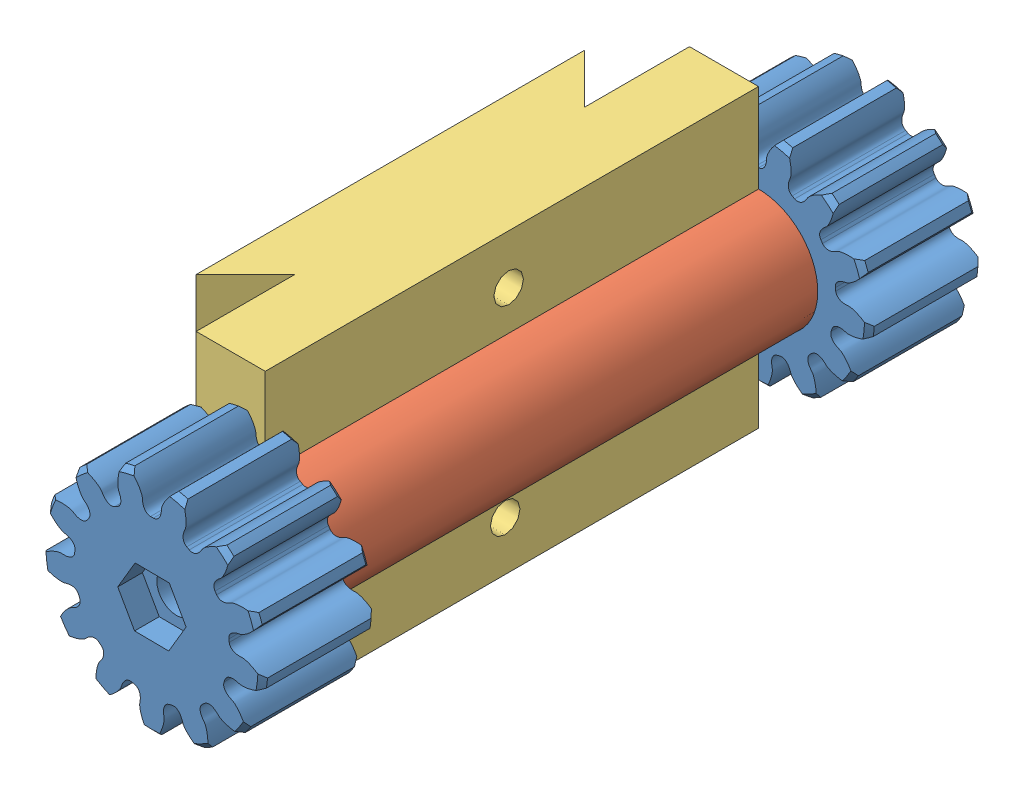
SolidWorks assembly Assy, configuration По умолчанию. Lengths in mm.
Overall size (24.71 30 73).
4 component instances, 3 part files, 5 mates.
Components (placement in the parent):
- Gear_1-1: Gear_1 [Výchozí] at (3.8868 4.0547 -7.9408) size (22.5 22.5 11.5)
- axle_spacer-1: axle_spacer [По умолчанию] at (3.872 3.9832 -11.1908) x (0 0 -1) z (0.485837 -0.87405 0) size (54 12 12)
- axle_cover_holder_1_2-1: axle_cover_holder_1_2 [По умолчанию] at (-3.128 -11.0168 -63.6908) x (0 0 1) z (-1 0 0) size (50 30 12)
- Gear_1-2: Gear_1 [Výchozí] at (3.872 3.9832 -69.4408) x (-0.103375 -0.994642 0) z (0 0 -1) size (22.5 22.5 11.5)
Mates (geometry in assembly coordinates):
- Угол1: planar angle = 0 rad: plane of axle_spacer-1 through (3.872 3.9832 -11.1908) normal (0 0 1); plane of Gear_1-1 through (3.8868 4.0547 -12.1908) normal (0 0 -1)
- Концентричный1: concentric: cylinder of axle_spacer-1 through (3.872 3.9832 -65.1908) axis (0 0 1) radius 6; cylinder of axle_cover_holder_1_2-1 through (3.872 3.9832 -13.6908) axis (0 0 -1) radius 6
- Концентричный3: concentric: cylinder of axle_spacer-1 through (3.872 3.9832 -65.1908) axis (0 0 1) radius 6; cylinder of Gear_1-2 through (3.872 3.9832 -65.1908) axis (0 0 1) radius 6
- Совпадение3: coincident: circle of axle_spacer-1; plane of Gear_1-2 through (3.872 3.9832 -65.1908) normal (0 0 1)
- Совпадение4: coincident: plane of axle_cover_holder_1_2-1 through (-8.128 -11.0168 -63.6908) normal (0 0 -1); plane of Gear_1-2 through (3.872 3.9832 -63.6908) normal (0 0 1)
